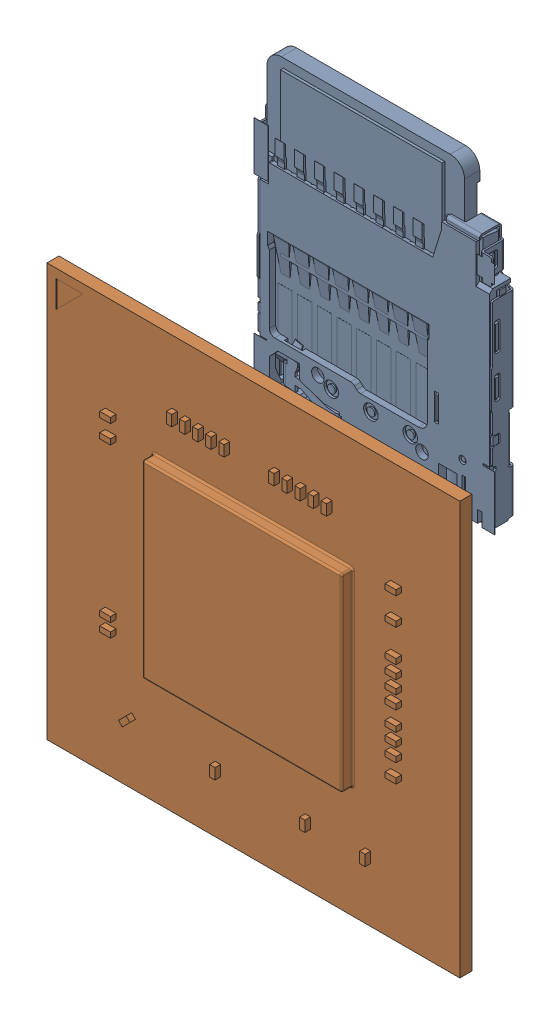
SolidWorks assembly 142-13448-1000-A02_ASM, configuration 142-13448-1000-A02_ASM. Lengths in mm.
Overall size (23 37.01 4.01).
2 component instances, 2 part files, 0 mates.
Components (placement in the parent):
- 080-0051-000_3-1: 080-0051-000_3 [080-0051-000_3] at (28.331 29.139 0) x (-1 0 0) z (0 0 -1) size (13.4 17 1.28)
- TM670M-A2_1-1: TM670M-A2_1 [TM670M-A2_1] at (23.7 13.45 1.2) size (23 23 1.29)
